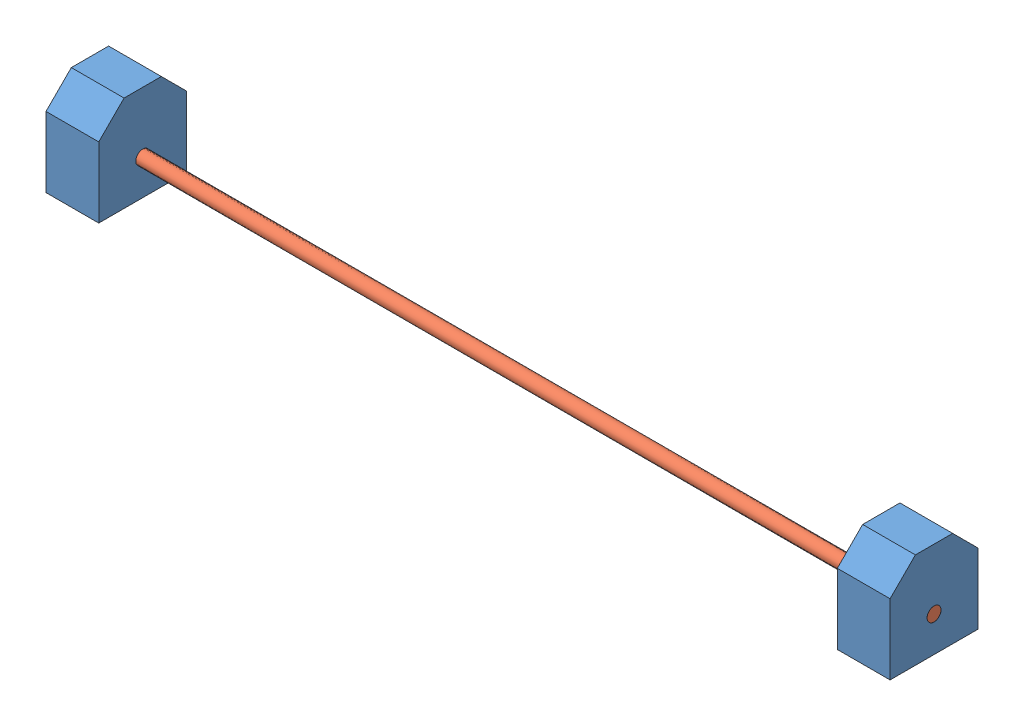
SolidWorks assembly M02, configuration Valor predeterminado. Lengths in mm.
Overall size (480 54.15 50).
3 component instances, 2 part files, 3 mates.
Components (placement in the parent):
- S01-1: S01 [Valor predeterminado] at (-12.7479 -12.5027 61.6506) size (30 54.15 50)
- B01-1: B01 [Valor predeterminado] at (-237.7479 -12.5027 61.6506) x (0 -0.924225 -0.381849) z (1 0 0) size (7.94 7.94 480)
- S01-2: S01 [Valor predeterminado] at (-462.7479 -12.5027 61.6506) size (30 54.15 50)
Mates (geometry in assembly coordinates):
- Coincidente1: coincident: circle of S01-1; circle of B01-1
- Coincidente3: coincident: circle of B01-1; circle of S01-2
- Paralelo2: parallel: plane of S01-1 through (-27.7479 -12.5027 61.6506) normal (-1 0 0); plane of S01-2 through (-447.7479 -12.5027 61.6506) normal (1 0 0)
